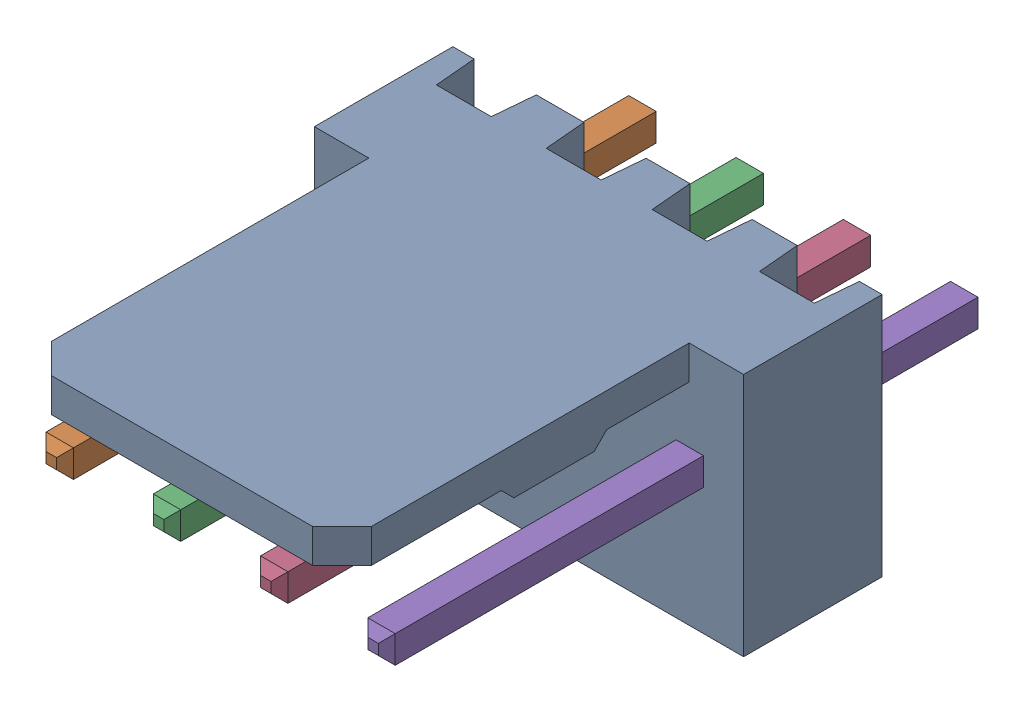
SolidWorks assembly Molex PCB 4 pin v3_5, configuration Default. Lengths in mm.
Overall size (10.16 5.79 14.92).
5 component instances, 2 part files, 0 mates.
Components (placement in the parent):
- BASE9710016-1: BASE9710016 [Default] at (2.54 2.895 -8.22) size (10.16 5.79 11.5)
- PINO9710016-1: PINO9710016 [Default] at (1.27 3.325 -0.72) size (0.65 0.65 14.2)
- PINO9710016-2: PINO9710016 [Default] at (3.81 3.325 -0.72) size (0.65 0.65 14.2)
- PINO9710016-3: PINO9710016 [Default] at (6.35 3.325 -0.72) size (0.65 0.65 14.2)
- PINO9710016-4: PINO9710016 [Default] at (8.89 3.325 -0.72) size (0.65 0.65 14.2)
